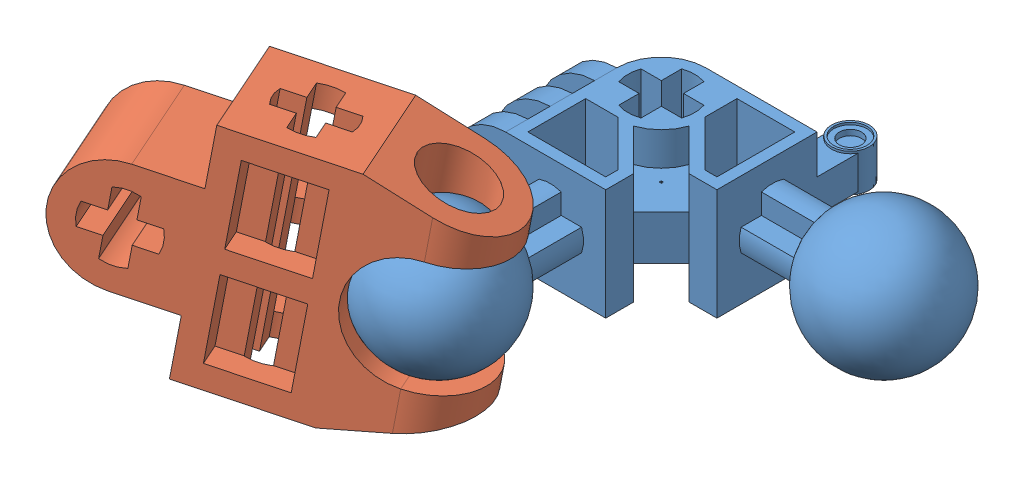
SolidWorks assembly Assem2, configuration Default. Lengths in mm.
Overall size (25.82 12.27 23.11).
2 component instances, 2 part files, 1 mates.
Components (placement in the parent):
- link 2x2-1: link 2x2 [Default] at (1.6237 9.0489 10.6785) size (17.5 6 18.1)
- the hand-1: the hand [Default] at (-1.6906 9.2783 19.4691) x (0.107038 0.988607 -0.105826) z (0.89713 -0.141916 -0.41835) size (10 5 15)
Mates (geometry in assembly coordinates):
- Concentric1: concentric: sphere of link 2x2-1; sphere of the hand-1
